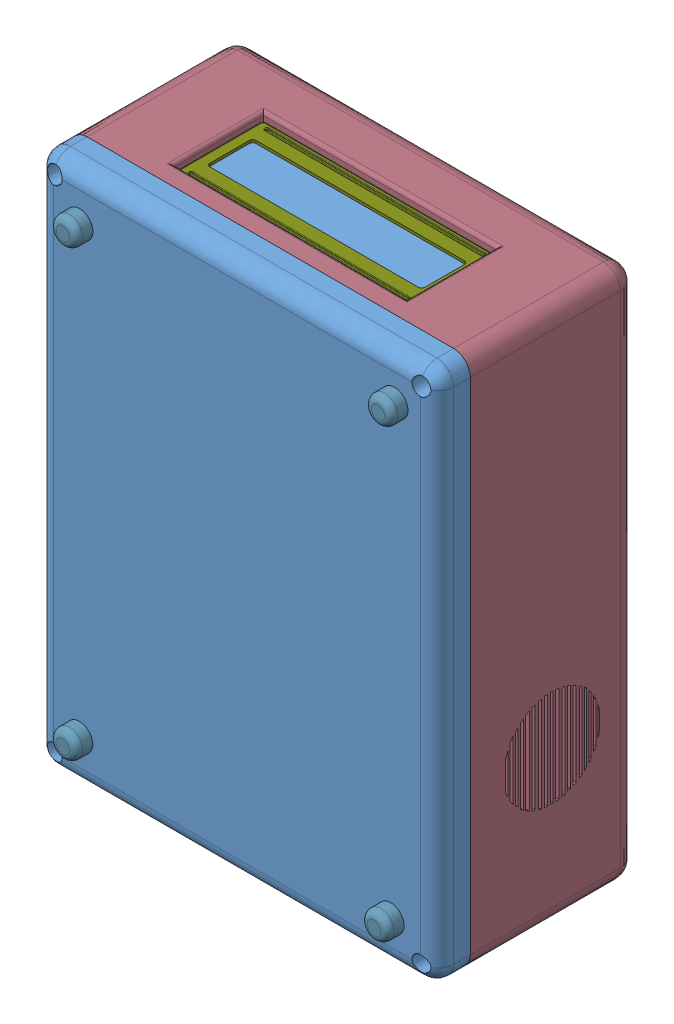
SolidWorks assembly Final enclosure for alarm clock, configuration Default. Lengths in mm.
Overall size (120 160 92.06).
262 component instances, 70 part files, 43 mates.
Components (placement in the parent):
- base-1: base [Default] at (30.3532 151.9666 91.7947) size (120 160 10)
- pin-8: pin [Default] at (46.9943 121.1307 93.7947) x (-0.999904 0.013854 0) z (0 0 -1) size (10 10 11.36)
- pin-9: pin [Default] at (96.9053 120.7497 93.7947) x (-0.30944 0.950919 0) z (0 0 -1) size (10 10 11.36)
- pin-10: pin [Default] at (46.2323 24.8647 93.7947) x (-0.51839 0.855144 0) z (0 0 -1) size (10 10 11.36)
- pin-11: pin [Default] at (99.0643 23.5947 93.7947) x (-0.211166 0.97745 0) z (0 0 -1) size (10 10 11.36)
- cct-4: cct [Default] at (154.3093 164.9457 90.0232) x (0 -1 0) z (0 0 -1) size (104.39 59.56 29)
  - Alarm_Clock.step-1: Alarm_Clock.step [Default] at origin size (104.39 59.56 29)
    - Board.step-1: Board.step [Default] at origin size (104.39 59.56 0.41)
      - Open CASCADE STEP translator 6.8 1.1.1.step-1: Open CASCADE STEP translator 6.8 1.1.1.step [Default] at (0 0 -0.4115) size (104.39 59.56 0.41)
    - P6.step-1: P6.step [Default] at origin size (15.65 5.57 13.08)
      - 66200411122.step-1: 66200411122.step [Default] at (71.0674 60.0699 4.98) x (1 0 0) z (0 1 0) size (15.65 13.08 5.57)
        - 6620xx11122_PIN.step-1: 6620xx11122_PIN.step [Default] at (-4.5 1.3806 0.255) x (-1 0 0) z (0 0 -1) size (0.64 10.1 0.9)
        - 6620xx11122_PIN.step-2: 6620xx11122_PIN.step [Default] at (-1.5 1.3806 0.255) size (0.64 10.1 0.9)
        - 6620xx11122_PIN.step-3: 6620xx11122_PIN.step [Default] at (1.5 1.3806 0.255) x (-1 0 0) z (0 0 -1) size (0.64 10.1 0.9)
        - 6620xx11122_PIN.step-4: 6620xx11122_PIN.step [Default] at (4.5 1.3806 0.255) size (0.64 10.1 0.9)
        - 66200411122-0.step-1: 66200411122-0.step [Default] at origin size (15.65 11 5.57)
    - U2.step-1: U2.step [Default] at origin size (7.2 35.3 4.58)
      - 5917139056.step-1: 5917139056.step [Default] at (93.091 78.74 0) size (7.2 35.3 4.58)
        - Extruded.step-1: Extruded.step [Default] at origin size (7.2 35.3 4.58)
    - U1.step-1: U1.step [Default] at origin size (10.5 4.7 16.2)
      - 5917143376.step-1: 5917143376.step [Default] at (61.468 81.322 3.5) size (10.5 4.7 9.55)
        - Extruded-1.step-1: Extruded-1.step [Default] at origin size (10.5 4.7 9.55)
      - 5917143056.step-1: 5917143056.step [Default] at (61.468 82.972 13.05) size (10.4 1.3 6.65)
        - Extruded-2.step-1: Extruded-2.step [Default] at origin size (10.4 1.3 6.65)
    - SW1.step-1: SW1.step [Default] at origin size (7.8 5.99 8.11)
      - Switch_TE_1825910-2_eec.step-1: Switch_TE_1825910-2_eec.step [Default] at (81.407 101.6 0) size (7.8 5.99 8.11)
        - Body.step-1: Body.step [Default] at (0 0 4.3) x (0 -1 0) z (0 0 1) size (5.99 5.99 3.9)
        - button.step-1: button.step [Default] at (0 0 4.3) x (0 -1 0) z (0 0 1) size (3.51 3.51 1.1)
        - cover.step-1: cover.step [Default] at (0 0 4.3) x (0 -1 0) z (0 0 1) size (5.99 5.99 0.1)
        - leads.step-1: leads.step [Default] at (0 0 4.3) x (0 -1 0) z (0 0 1) size (5.21 7.8 4.81)
        - circle.step-1: circle.step [Default] at (-2.6803 2.6863 3.6) size (0.4 0.4 0)
        - TE_Connectivity.step-1: TE_Connectivity.step [Default] at (-0.1925 -2.4218 3.6) size (2.27 0.85 0.01)
    - R9.step-1: R9.step [Default] at origin size (3.9 15.83 5.9)
      - 5917146656.step-1: 5917146656.step [Default] at (131.699 58.921 1.95) x (0 0 -1) z (0 1 0) size (0.83 0.83 15)
        - Cylinder.step-1: Cylinder.step [Default] at origin size (0.83 0.83 15)
      - 5917146416.step-1: 5917146416.step [Default] at (131.6989 73.9211 1.95) x (0 1 0) z (0 0 1) size (0.83 0.83 0.83)
        - Sphere.step-1: Sphere.step [Default] at origin size (0.83 0.83 0.83)
      - 5917146416.step-2: 5917146416.step [Default] at (131.699 58.921 1.95) x (0 1 0) z (0 0 1) size (0.83 0.83 0.83)
        - Sphere.step-1: Sphere.step [Default] at origin size (0.83 0.83 0.83)
      - 5917146016.step-1: 5917146016.step [Default] at (131.6989 73.9211 -2) x (0 1 0) z (0 0 1) size (0.83 0.83 3.95)
        - Cylinder-3.step-1: Cylinder-3.step [Default] at origin size (0.83 0.83 3.95)
      - 5917146016.step-2: 5917146016.step [Default] at (131.699 58.9211 -2) x (0 1 0) z (0 0 1) size (0.83 0.83 3.95)
        - Cylinder-3.step-1: Cylinder-3.step [Default] at origin size (0.83 0.83 3.95)
      - 5917145616.step-1: 5917145616.step [Default] at (131.699 61.4209 1.95) x (0 0 -1) z (0 1 0) size (3.9 3.9 10)
        - Cylinder-4.step-1: Cylinder-4.step [Default] at origin size (3.9 3.9 10)
    - R8.step-1: R8.step [Default] at origin size (3.9 15.83 5.9)
      - 5917145616.step-1: 5917145616.step [Default] at (118.745 61.4209 1.95) x (0 0 -1) z (0 1 0) size (3.9 3.9 10)
        - Cylinder-4.step-1: Cylinder-4.step [Default] at origin size (3.9 3.9 10)
      - 5917146016.step-1: 5917146016.step [Default] at (118.745 58.9211 -2) x (0 1 0) z (0 0 1) size (0.83 0.83 3.95)
        - Cylinder-3.step-1: Cylinder-3.step [Default] at origin size (0.83 0.83 3.95)
      - 5917146016.step-2: 5917146016.step [Default] at (118.7449 73.9211 -2) x (0 1 0) z (0 0 1) size (0.83 0.83 3.95)
        - Cylinder-3.step-1: Cylinder-3.step [Default] at origin size (0.83 0.83 3.95)
      - 5917146416.step-1: 5917146416.step [Default] at (118.745 58.921 1.95) x (0 1 0) z (0 0 1) size (0.83 0.83 0.83)
        - Sphere.step-1: Sphere.step [Default] at origin size (0.83 0.83 0.83)
      - 5917146416.step-2: 5917146416.step [Default] at (118.7449 73.9211 1.95) x (0 1 0) z (0 0 1) size (0.83 0.83 0.83)
        - Sphere.step-1: Sphere.step [Default] at origin size (0.83 0.83 0.83)
      - 5917146656.step-1: 5917146656.step [Default] at (118.745 58.921 1.95) x (0 0 -1) z (0 1 0) size (0.83 0.83 15)
        - Cylinder.step-1: Cylinder.step [Default] at origin size (0.83 0.83 15)
    - R7.step-1: R7.step [Default] at origin size (3.9 15.83 5.9)
      - 5917145616.step-1: 5917145616.step [Default] at (125.476 61.2939 1.95) x (0 0 -1) z (0 1 0) size (3.9 3.9 10)
        - Cylinder-4.step-1: Cylinder-4.step [Default] at origin size (3.9 3.9 10)
      - 5917146016.step-1: 5917146016.step [Default] at (125.476 58.7941 -2) x (0 1 0) z (0 0 1) size (0.83 0.83 3.95)
        - Cylinder-3.step-1: Cylinder-3.step [Default] at origin size (0.83 0.83 3.95)
      - 5917146016.step-2: 5917146016.step [Default] at (125.4759 73.7941 -2) x (0 1 0) z (0 0 1) size (0.83 0.83 3.95)
        - Cylinder-3.step-1: Cylinder-3.step [Default] at origin size (0.83 0.83 3.95)
      - 5917146416.step-1: 5917146416.step [Default] at (125.476 58.794 1.95) x (0 1 0) z (0 0 1) size (0.83 0.83 0.83)
        - Sphere.step-1: Sphere.step [Default] at origin size (0.83 0.83 0.83)
      - 5917146416.step-2: 5917146416.step [Default] at (125.4759 73.7941 1.95) x (0 1 0) z (0 0 1) size (0.83 0.83 0.83)
        - Sphere.step-1: Sphere.step [Default] at origin size (0.83 0.83 0.83)
      - 5917146656.step-1: 5917146656.step [Default] at (125.476 58.794 1.95) x (0 0 -1) z (0 1 0) size (0.83 0.83 15)
        - Cylinder.step-1: Cylinder.step [Default] at origin size (0.83 0.83 15)
    - R6.step-1: R6.step [Default] at origin size (3.9 15.83 5.9)
      - 5917145616.step-1: 5917145616.step [Default] at (138.43 61.3009 1.95) x (0 0 -1) z (0 1 0) size (3.9 3.9 10)
        - Cylinder-4.step-1: Cylinder-4.step [Default] at origin size (3.9 3.9 10)
      - 5917146016.step-1: 5917146016.step [Default] at (138.43 58.8011 -2) x (0 1 0) z (0 0 1) size (0.83 0.83 3.95)
        - Cylinder-3.step-1: Cylinder-3.step [Default] at origin size (0.83 0.83 3.95)
      - 5917146016.step-2: 5917146016.step [Default] at (138.4299 73.8011 -2) x (0 1 0) z (0 0 1) size (0.83 0.83 3.95)
        - Cylinder-3.step-1: Cylinder-3.step [Default] at origin size (0.83 0.83 3.95)
      - 5917146416.step-1: 5917146416.step [Default] at (138.43 58.801 1.95) x (0 1 0) z (0 0 1) size (0.83 0.83 0.83)
        - Sphere.step-1: Sphere.step [Default] at origin size (0.83 0.83 0.83)
      - 5917146416.step-2: 5917146416.step [Default] at (138.4299 73.8011 1.95) x (0 1 0) z (0 0 1) size (0.83 0.83 0.83)
        - Sphere.step-1: Sphere.step [Default] at origin size (0.83 0.83 0.83)
      - 5917146656.step-1: 5917146656.step [Default] at (138.43 58.801 1.95) x (0 0 -1) z (0 1 0) size (0.83 0.83 15)
        - Cylinder.step-1: Cylinder.step [Default] at origin size (0.83 0.83 15)
    - R5.step-1: R5.step [Default] at origin size (15.83 3.9 5.9)
      - 5919244592.step-1: 5919244592.step [Default] at (63.634 105.156 1.95) x (0 0 -1) z (-1 0 0) size (0.83 0.83 15)
        - Cylinder-5.step-1: Cylinder-5.step [Default] at origin size (0.83 0.83 15)
      - 5919245152.step-1: 5919245152.step [Default] at (48.6339 105.1559 1.95) x (-1 0 0) z (0 0 1) size (0.83 0.83 0.83)
        - Sphere-6.step-1: Sphere-6.step [Default] at origin size (0.83 0.83 0.83)
      - 5919245152.step-2: 5919245152.step [Default] at (63.634 105.156 1.95) x (-1 0 0) z (0 0 1) size (0.83 0.83 0.83)
        - Sphere-6.step-1: Sphere-6.step [Default] at origin size (0.83 0.83 0.83)
      - 5919245872.step-1: 5919245872.step [Default] at (48.6339 105.1559 -2) x (-1 0 0) z (0 0 1) size (0.83 0.83 3.95)
        - Cylinder-7.step-1: Cylinder-7.step [Default] at origin size (0.83 0.83 3.95)
      - 5919245872.step-2: 5919245872.step [Default] at (63.6339 105.156 -2) x (-1 0 0) z (0 0 1) size (0.83 0.83 3.95)
        - Cylinder-7.step-1: Cylinder-7.step [Default] at origin size (0.83 0.83 3.95)
      - 5919246432.step-1: 5919246432.step [Default] at (61.1341 105.156 1.95) x (0 0 -1) z (-1 0 0) size (3.9 3.9 10)
        - Cylinder-8.step-1: Cylinder-8.step [Default] at origin size (3.9 3.9 10)
    - R4.step-1: R4.step [Default] at origin size (15.83 3.9 5.9)
      - 5919246432.step-1: 5919246432.step [Default] at (138.0961 79.756 1.95) x (0 0 -1) z (-1 0 0) size (3.9 3.9 10)
        - Cylinder-8.step-1: Cylinder-8.step [Default] at origin size (3.9 3.9 10)
      - 5919245872.step-1: 5919245872.step [Default] at (140.5959 79.756 -2) x (-1 0 0) z (0 0 1) size (0.83 0.83 3.95)
        - Cylinder-7.step-1: Cylinder-7.step [Default] at origin size (0.83 0.83 3.95)
      - 5919245872.step-2: 5919245872.step [Default] at (125.5959 79.7559 -2) x (-1 0 0) z (0 0 1) size (0.83 0.83 3.95)
        - Cylinder-7.step-1: Cylinder-7.step [Default] at origin size (0.83 0.83 3.95)
      - 5919245152.step-1: 5919245152.step [Default] at (140.5959 79.756 1.95) x (-1 0 0) z (0 0 1) size (0.83 0.83 0.83)
        - Sphere-6.step-1: Sphere-6.step [Default] at origin size (0.83 0.83 0.83)
      - 5919245152.step-2: 5919245152.step [Default] at (125.5959 79.7559 1.95) x (-1 0 0) z (0 0 1) size (0.83 0.83 0.83)
        - Sphere-6.step-1: Sphere-6.step [Default] at origin size (0.83 0.83 0.83)
      - 5919244592.step-1: 5919244592.step [Default] at (140.596 79.756 1.95) x (0 0 -1) z (-1 0 0) size (0.83 0.83 15)
        - Cylinder-5.step-1: Cylinder-5.step [Default] at origin size (0.83 0.83 15)
    - R1.step-1: R1.step [Default] at origin size (15.83 3.9 5.9)
      - 5919244592.step-1: 5919244592.step [Default] at (74.168 100.457 1.95) x (0 0 -1) z (-1 0 0) size (0.83 0.83 15)
        - Cylinder-5.step-1: Cylinder-5.step [Default] at origin size (0.83 0.83 15)
      - 5919245152.step-1: 5919245152.step [Default] at (59.1679 100.4569 1.95) x (-1 0 0) z (0 0 1) size (0.83 0.83 0.83)
        - Sphere-6.step-1: Sphere-6.step [Default] at origin size (0.83 0.83 0.83)
      - 5919245152.step-2: 5919245152.step [Default] at (74.168 100.457 1.95) x (-1 0 0) z (0 0 1) size (0.83 0.83 0.83)
        - Sphere-6.step-1: Sphere-6.step [Default] at origin size (0.83 0.83 0.83)
      - 5919245872.step-1: 5919245872.step [Default] at (59.1679 100.4569 -2) x (-1 0 0) z (0 0 1) size (0.83 0.83 3.95)
        - Cylinder-7.step-1: Cylinder-7.step [Default] at origin size (0.83 0.83 3.95)
      - 5919245872.step-2: 5919245872.step [Default] at (74.1679 100.457 -2) x (-1 0 0) z (0 0 1) size (0.83 0.83 3.95)
        - Cylinder-7.step-1: Cylinder-7.step [Default] at origin size (0.83 0.83 3.95)
      - 5919246432.step-1: 5919246432.step [Default] at (71.6681 100.457 1.95) x (0 0 -1) z (-1 0 0) size (3.9 3.9 10)
        - Cylinder-8.step-1: Cylinder-8.step [Default] at origin size (3.9 3.9 10)
    - Q1.step-1: Q1.step [Default] at origin size (4.79 3.67 5.95)
      - 5917134816.step-1: 5917134816.step [Default] at (121.793 99.457 2.54) size (4.79 3.67 5.95)
        - Extruded-9.step-1: Extruded-9.step [Default] at origin size (4.79 3.67 5.95)
    - P5.step-1: P5.step [Default] at origin size (5.08 5.8 15.26)
      - 022272021.step-1: 022272021.step [Default] at (132.9691 104.0131 1.6) x (1 0 0) z (0 -1 0) size (5.08 15.26 5.8)
        - Open CASCADE STEP translator 6.8 1.14.1.1.step-1: Open CASCADE STEP translator 6.8 1.14.1.1.step [Default] at origin size (5.08 15.26 5.8)
        - Open CASCADE STEP translator 6.8 1.14.1.2.step-1: Open CASCADE STEP translator 6.8 1.14.1.2.step [Default] at origin
    - P4.step-1: P4.step [Default] at origin size (5.57 21.65 13.75)
      - 66200611122.step-1: 66200611122.step [Default] at (108.0759 64.1086 4.98) x (0 -1 0) z (1 0 0) size (21.65 13.75 5.57)
        - 6620xx11122_PIN-10.step-1: 6620xx11122_PIN-10.step [Default] at (-7.5 1.3806 0.255) x (-1 0 0) z (0 0 -1) size (0.64 10.1 0.9)
        - 6620xx11122_PIN-10.step-2: 6620xx11122_PIN-10.step [Default] at (-4.5 1.3806 0.255) size (0.64 10.1 0.9)
        - 6620xx11122_PIN-10.step-3: 6620xx11122_PIN-10.step [Default] at (-1.5 2.0477 0.25) x (-1 0 0) z (0 0 -1) size (0.64 10.1 0.9)
        - 6620xx11122_PIN-10.step-4: 6620xx11122_PIN-10.step [Default] at (1.5 2.0477 0.25) size (0.64 10.1 0.9)
        - 6620xx11122_PIN-10.step-5: 6620xx11122_PIN-10.step [Default] at (4.5 2.0477 0.25) x (-1 0 0) z (0 0 -1) size (0.64 10.1 0.9)
        - 6620xx11122_PIN-10.step-6: 6620xx11122_PIN-10.step [Default] at (7.5 2.0477 0.25) size (0.64 10.1 0.9)
        - 66200611122-11.step-1: 66200611122-11.step [Default] at origin size (21.65 11 5.57)
    - P3.step-1: P3.step [Default] at origin size (5.57 24.65 13.75)
      - 66200711122.step-1: 66200711122.step [Default] at (110.1101 90.3304 4.98) x (0 1 0) z (-1 0 0) size (24.65 13.75 5.57)
        - 6620xx11122_PIN-12.step-1: 6620xx11122_PIN-12.step [Default] at (-9 1.3806 0.255) x (-1 0 0) z (0 0 -1) size (0.64 10.1 0.9)
        - 6620xx11122_PIN-12.step-2: 6620xx11122_PIN-12.step [Default] at (-6 1.3806 0.255) size (0.64 10.1 0.9)
        - 6620xx11122_PIN-12.step-3: 6620xx11122_PIN-12.step [Default] at (-3 2.0477 0.25) x (-1 0 0) z (0 0 -1) size (0.64 10.1 0.9)
        - 6620xx11122_PIN-12.step-4: 6620xx11122_PIN-12.step [Default] at (0 2.0477 0.25) size (0.64 10.1 0.9)
        - 6620xx11122_PIN-12.step-5: 6620xx11122_PIN-12.step [Default] at (3 2.0477 0.25) x (-1 0 0) z (0 0 -1) size (0.64 10.1 0.9)
        - 6620xx11122_PIN-12.step-6: 6620xx11122_PIN-12.step [Default] at (6 2.0477 0.25) size (0.64 10.1 0.9)
        - 6620xx11122_PIN-12.step-7: 6620xx11122_PIN-12.step [Default] at (9 2.0477 0.25) x (-1 0 0) z (0 0 -1) size (0.64 10.1 0.9)
        - 66200711122-13.step-1: 66200711122-13.step [Default] at origin size (24.65 11 5.57)
    - P2.step-1: P2.step [Default] at origin size (39.65 5.57 13.08)
      - 66201211122.step-1: 66201211122.step [Default] at (63.6486 91.8221 4.98) x (-1 0 0) z (0 -1 0) size (39.65 13.08 5.57)
        - 6620xx11122_PIN-14.step-1: 6620xx11122_PIN-14.step [Default] at (-16.5 1.3806 0.255) x (-1 0 0) z (0 0 -1) size (0.64 10.1 0.9)
        - 6620xx11122_PIN-14.step-2: 6620xx11122_PIN-14.step [Default] at (-13.5 1.3806 0.255) size (0.64 10.1 0.9)
        - 6620xx11122_PIN-14.step-3: 6620xx11122_PIN-14.step [Default] at (-10.5 1.3806 0.255) x (-1 0 0) z (0 0 -1) size (0.64 10.1 0.9)
        - 6620xx11122_PIN-14.step-4: 6620xx11122_PIN-14.step [Default] at (-4.5 1.3806 0.255) x (-1 0 0) z (0 0 -1) size (0.64 10.1 0.9)
        - 6620xx11122_PIN-14.step-5: 6620xx11122_PIN-14.step [Default] at (1.5 1.3806 0.255) x (-1 0 0) z (0 0 -1) size (0.64 10.1 0.9)
        - 6620xx11122_PIN-14.step-6: 6620xx11122_PIN-14.step [Default] at (7.5 1.3806 0.255) x (-1 0 0) z (0 0 -1) size (0.64 10.1 0.9)
        - 6620xx11122_PIN-14.step-7: 6620xx11122_PIN-14.step [Default] at (13.5 1.3806 0.255) x (-1 0 0) z (0 0 -1) size (0.64 10.1 0.9)
        - 6620xx11122_PIN-14.step-8: 6620xx11122_PIN-14.step [Default] at (-7.5 1.3806 0.255) size (0.64 10.1 0.9)
        - 6620xx11122_PIN-14.step-9: 6620xx11122_PIN-14.step [Default] at (-1.5 1.3806 0.255) size (0.64 10.1 0.9)
        - 6620xx11122_PIN-14.step-10: 6620xx11122_PIN-14.step [Default] at (4.5 1.3806 0.255) size (0.64 10.1 0.9)
        - 6620xx11122_PIN-14.step-11: 6620xx11122_PIN-14.step [Default] at (10.5 1.3806 0.255) size (0.64 10.1 0.9)
        - 6620xx11122_PIN-14.step-12: 6620xx11122_PIN-14.step [Default] at (16.5 1.3806 0.255) size (0.64 10.1 0.9)
        - 66201211122-15.step-1: 66201211122-15.step [Default] at origin size (39.65 11 5.57)
    - P1.step-1: P1.step [Default] at origin size (5.08 5.8 15.26)
      - 022272021.step-1: 022272021.step [Default] at (46.3549 81.4069 1.6) x (-1 0 0) z (0 1 0) size (5.08 15.26 5.8)
        - Open CASCADE STEP translator 6.8 1.14.1.1.step-1: Open CASCADE STEP translator 6.8 1.14.1.1.step [Default] at origin size (5.08 15.26 5.8)
        - Open CASCADE STEP translator 6.8 1.14.1.2.step-1: Open CASCADE STEP translator 6.8 1.14.1.2.step [Default] at origin
    - LS1.step-1: LS1.step [Default] at origin size (16 16 13.9)
      - Speak_TDK_SDC1610M5-01_eec.step-1: Speak_TDK_SDC1610M5-01_eec.step [Default] at (131.231 90.424 0) size (16 16 13.9)
        - 1.step-1: 1.step [Default] at origin size (5.8 0.8 4.4)
        - 2.step-1: 2.step [Default] at origin size (5 5 0.5)
        - 3.step-1: 3.step [Default] at origin size (16 16 10)
        - TDK_Logo.step-1: TDK_Logo.step [Default] at (0.0013 6.3762 9.999) size (4.12 1.23 0)
    - D1.step-1: D1.step [Default] at origin size (1.91 8.12 5.91)
      - Diode_ON_Semiconductor_1N914B_eec.step-1: Diode_ON_Semiconductor_1N914B_eec.step [Default] at (118.618 88.9 0) x (0 1 0) z (0 0 1) size (8.12 1.91 5.91)
        - 1-16.step-1: 1-16.step [Default] at (0 -0.955 0.955) size (0.88 1.91 1.91)
        - 2-17.step-1: 2-17.step [Default] at (0 -0.955 0.955) size (8.12 0.7 5.3)
        - 3-18.step-1: 3-18.step [Default] at (0 -0.955 0.955) size (3.8 1.91 1.91)
        - 4.step-1: 4.step [Default] at (0 -0.955 0.955) size (0.45 0.45 0.96)
    - C5.step-1: C5.step [Default] at origin size (2.54 3.81 11.66)
      - 5917146896.step-1: 5917146896.step [Default] at (72.3899 68.5801 -7) size (0.51 0.51 7)
        - Extruded-19.step-1: Extruded-19.step [Default] at origin size (0.51 0.51 7)
      - 5917146896.step-2: 5917146896.step [Default] at (72.39 71.1201 -7) size (0.51 0.51 7)
        - Extruded-19.step-1: Extruded-19.step [Default] at origin size (0.51 0.51 7)
      - 5917140256.step-1: 5917140256.step [Default] at (72.39 69.85 0) size (2.54 3.81 4.66)
        - Extruded-20.step-1: Extruded-20.step [Default] at origin size (2.54 3.81 4.66)
    - C4.step-1: C4.step [Default] at origin size (2.54 3.81 11.66)
      - 5917146896.step-1: 5917146896.step [Default] at (72.3899 78.1051 -7) size (0.51 0.51 7)
        - Extruded-19.step-1: Extruded-19.step [Default] at origin size (0.51 0.51 7)
      - 5917146896.step-2: 5917146896.step [Default] at (72.39 80.6451 -7) size (0.51 0.51 7)
        - Extruded-19.step-1: Extruded-19.step [Default] at origin size (0.51 0.51 7)
      - 5917140256.step-1: 5917140256.step [Default] at (72.39 79.375 0) size (2.54 3.81 4.66)
        - Extruded-20.step-1: Extruded-20.step [Default] at origin size (2.54 3.81 4.66)
    - C3.step-1: C3.step [Default] at origin size (8 8 25)
      - 5917142176.step-1: 5917142176.step [Default] at (97.7901 103.6321 -3) size (0.6 0.6 3)
        - Cylinder-21.step-1: Cylinder-21.step [Default] at origin size (0.6 0.6 3)
      - 5917141696.step-1: 5917141696.step [Default] at (101.29 103.6321 -2) size (0.6 0.6 2)
        - Cylinder-22.step-1: Cylinder-22.step [Default] at origin size (0.6 0.6 2)
      - 5917141296.step-1: 5917141296.step [Default] at (99.5401 103.6321 0) size (8 8 22)
        - Cylinder-23.step-1: Cylinder-23.step [Default] at origin size (8 8 22)
    - C2.step-1: C2.step [Default] at origin size (8 8 25)
      - 5917141056.step-1: 5917141056.step [Default] at (58.6741 69.6239 0) x (0 -1 0) z (0 0 1) size (8 8 22)
        - Cylinder-24.step-1: Cylinder-24.step [Default] at origin size (8 8 22)
      - 5917140816.step-1: 5917140816.step [Default] at (58.6741 67.874 -2) x (0 -1 0) z (0 0 1) size (0.6 0.6 2)
        - Cylinder-25.step-1: Cylinder-25.step [Default] at origin size (0.6 0.6 2)
      - 5917140576.step-1: 5917140576.step [Default] at (58.6741 71.3739 -3) x (0 -1 0) z (0 0 1) size (0.6 0.6 3)
        - Cylinder-26.step-1: Cylinder-26.step [Default] at origin size (0.6 0.6 3)
    - C1.step-1: C1.step [Default] at origin size (8 8 25)
      - 5917141056.step-1: 5917141056.step [Default] at (46.6091 69.6239 0) x (0 -1 0) z (0 0 1) size (8 8 22)
        - Cylinder-24.step-1: Cylinder-24.step [Default] at origin size (8 8 22)
      - 5917140816.step-1: 5917140816.step [Default] at (46.6091 67.874 -2) x (0 -1 0) z (0 0 1) size (0.6 0.6 2)
        - Cylinder-25.step-1: Cylinder-25.step [Default] at origin size (0.6 0.6 2)
      - 5917140576.step-1: 5917140576.step [Default] at (46.6091 71.3739 -3) x (0 -1 0) z (0 0 1) size (0.6 0.6 3)
        - Cylinder-26.step-1: Cylinder-26.step [Default] at origin size (0.6 0.6 3)
- 9V Battery Holder-2: 9V Battery Holder [Default] at (137.4118 101.1961 96.7947) x (-1 0 0) z (0 -1 0) size (30 20 54)
- Battery-3: Battery [Default] at (122.6618 51.3064 84.1947) size (26.5 48 17.2)
- body assem-1: body assem [Default] at (15.0156 -32.943 164.5173) x (1 0 0) z (0 1 0) size (120 50 160)
  - body-1: body [Default] at (15.3376 122.7226 24.9096) size (120 50 160)
  - LCD-1: LCD [Default] at (75.9876 93.6226 173.2096) x (1 0 0) z (0 -1 0) size (80 18.3 36)
    - pcbboard-1: pcbboard [Default] at origin size (80 4.2 36)
    - 16pin_header__-1: 16pin_header__ [Default] at (-32 0 -15.5) x (0 0 1) z (1 0 0) size (2.54 11.5 40.64)
    - lcd window-1: lcd window [Default] at (0 9 1.5) size (71.3 11.8 27.44)
    - backlight-1: backlight [Default] at (0 1.7 1.5) x (-1 0 0) z (0 0 -1) size (74.38 2.98 18)
    - conductor-1: conductor [Default] at (0 1.7 12.6) size (69.7 5.5 3)
    - conductor-2: conductor [Default] at (0 1.7 -9.6) size (69.7 5.5 3)
    - liquid crystal grabcad-1: liquid crystal grabcad [Default] at (0 7.9 1.5) size (68.5 2.2 25)
    - smt_resistor222-1: smt_resistor222 [Default] at (-32.75 0 -5.25) x (0 0 1) z (1 0 0) size (1.8 0.6 4)
    - smt_resistor222-2: smt_resistor222 [Default] at (-32.75 0 -2.75) x (0 0 1) z (1 0 0) size (1.8 0.6 4)
    - smt_resistor222-3: smt_resistor222 [Default] at (-32.75 0 -0.25) x (0 0 1) z (1 0 0) size (1.8 0.6 4)
    - smt_resistor222-4: smt_resistor222 [Default] at (-32.75 0 2.25) x (0 0 1) z (1 0 0) size (1.8 0.6 4)
    - smt_resistor222-5: smt_resistor222 [Default] at (-32.75 0 4.75) x (0 0 1) z (1 0 0) size (1.8 0.6 4)
    - smt_resistor222-6: smt_resistor222 [Default] at (-32.75 0 7.25) x (0 0 1) z (1 0 0) size (1.8 0.6 4)
    - smt_resistor101-1: smt_resistor101 [Default] at (30.25 0 6.1) x (0 0 -1) z (-1 0 0) size (1.8 0.6 5.2)
    - smt_resistor101-2: smt_resistor101 [Default] at (30.25 0 2.85) x (0 0 -1) z (-1 0 0) size (1.8 0.6 5.2)
  - pin1 lcd-1: pin1 lcd [Default] at (113.4876 109.1226 170.0096) size (3 3 5)
  - pin1 lcd-2: pin1 lcd [Default] at (113.4876 78.1226 170.0096) size (3 3 5)
  - pin1 lcd-3: pin1 lcd [Default] at (38.4876 78.1226 170.0096) size (3 3 5)
  - pin1 lcd-4: pin1 lcd [Default] at (38.4876 109.1226 170.0096) size (3 3 5)
- KeyPad_3x4_w_pcb-1: KeyPad_3x4_w_pcb [Default] at (91.866 94.3035 38.7947) x (1 0 0) z (0 0 -1) size (51 69.5 10.29)
  - KeyPad_3x4_w_pcb.step-1: KeyPad_3x4_w_pcb.step [Default] at origin size (51 69.5 10.29)
    - Body_top.step-1: Body_top.step [Default] at origin size (46 56.8 3.6)
    - KeyPad.step-1: KeyPad.step [Default] at origin size (44.02 53.35 7.29)
    - Body_bottom.step-1: Body_bottom.step [Default] at origin size (51 63.8 3)
    - PCB_pads.step-1: PCB_pads.step [Default] at origin size (36.4 5.6 1.61)
    - PCB.step-1: PCB.step [Default] at origin size (36.5 5.7 1.6)
    - PCBtracks.step-1: PCBtracks.step [Default] at origin size (36.45 5.65 1.6)
    - KeyPad_collor.step-1: KeyPad_collor.step [Default] at origin size (40 50 6.89)
- Emergency Stop Button-2: Emergency Stop Button [Default] at (90.3533 26.9639 34.7353) x (0.999972 0.007536 0) z (-0.007536 0.999972 0) size (38.72 65.6 38.72)
- STP310400160-1: STP310400160 [Default] at (68.791 64.7287 37.5551) x (1 0 0) z (0 1 0) size (6.25 12.93 6.25)
- STP310400160-2: STP310400160 [Default] at (114.941 64.7287 37.5551) x (1 0 0) z (0 1 0) size (6.25 12.93 6.25)
- STP310400160-3: STP310400160 [Default] at (68.791 123.8787 37.5551) x (1 0 0) z (0 1 0) size (6.25 12.93 6.25)
- STP310400160-4: STP310400160 [Default] at (114.941 123.8787 37.5551) x (1 0 0) z (0 1 0) size (6.25 12.93 6.25)
- STP310400160-6: STP310400160 [Default] at (35.3531 -3.0336 98.0342) x (0.929608 -0.36855 0) z (-0.36855 -0.929608 0) size (6.25 12.93 6.25)
- STP310400160-7: STP310400160 [Default] at (145.3531 146.9664 98.0342) x (0.929608 -0.36855 0) z (-0.36855 -0.929608 0) size (6.25 12.93 6.25)
- STP310400160-9: STP310400160 [Default] at (35.3531 146.9664 98.0342) x (0.929608 -0.36855 0) z (-0.36855 -0.929608 0) size (6.25 12.93 6.25)
- STP310400160-10: STP310400160 [Default] at (145.3531 -3.0336 98.0342) x (0.929608 -0.36855 0) z (-0.36855 -0.929608 0) size (6.25 12.93 6.25)
- leg-5: leg [Default] at (43.0816 4.9248 106.7947) x (-0.998999 -0.044741 0) z (0 0 -1) size (8 8 5)
- leg-6: leg [Default] at (137.6443 139.0201 106.7947) x (-0.998999 -0.044741 0) z (0 0 -1) size (8 8 5)
- leg-7: leg [Default] at (136.4751 4.5046 106.7947) x (-0.998999 -0.044741 0) z (0 0 -1) size (8 8 5)
- leg-8: leg [Default] at (43.1186 138.1725 106.7947) x (-0.998999 -0.044741 0) z (0 0 -1) size (8 8 5)
- cover-1: cover [Default] at (109.9211 133.9035 40.1947) x (-1 0 0) z (0 0 -1) size (36.3 5.6 3.6)
Mates (geometry in assembly coordinates):
- Parallel5: parallel: plane of base-1 through (30.3532 151.9666 96.7947) normal (0 0 -1); plane of pin-8 through (46.9943 121.1307 96.7947) normal (0 0 1)
- Parallel6: parallel: plane of base-1 through (30.3532 151.9666 96.7947) normal (0 0 -1); plane of pin-9 through (96.9053 120.7497 96.7947) normal (0 0 1)
- Coincident18: coincident: plane of base-1 through (30.3532 151.9666 96.7947) normal (0 0 -1); plane of pin-9 through (96.9053 120.7497 96.7947) normal (0 0 1)
- Coincident19: coincident: plane of base-1 through (30.3532 151.9666 96.7947) normal (0 0 -1); plane of pin-9 through (96.9053 120.7497 96.7947) normal (0 0 1)
- Coincident20: coincident: plane of base-1 through (30.3532 151.9666 96.7947) normal (0 0 -1); plane of pin-8 through (46.9943 121.1307 96.7947) normal (0 0 1)
- Coincident21: coincident: plane of base-1 through (30.3532 151.9666 96.7947) normal (0 0 -1); plane of pin-10 through (46.2323 24.8647 96.7947) normal (0 0 1)
- Coincident22: coincident: plane of base-1 through (30.3532 151.9666 96.7947) normal (0 0 -1); circle of pin-11
- Concentric5: concentric: circle of pin-8; circle of cct-4/Alarm_Clock.step-1/Board.step-1/Open CASCADE STEP translator 6.8 1.1.1.step-1
- Concentric7: concentric: circle of pin-9; circle of cct-4/Alarm_Clock.step-1/Board.step-1/Open CASCADE STEP translator 6.8 1.1.1.step-1
- Coincident24: coincident: plane of pin-9 through (96.9053 120.7497 90.4347) normal (0 0 -1); plane of cct-4/Alarm_Clock.step-1/Board.step-1/Open CASCADE STEP translator 6.8 1.1.1.step-1 through (102.4933 124.9407 90.4347) normal (0 0 1)
- Coincident26: coincident: plane of base-1 through (30.3532 151.9666 96.7947) normal (0 0 -1); plane of 9V Battery Holder-2 through (137.4118 101.1961 96.7947) normal (0 0 1)
- Parallel8: parallel: line of base-1 through (140.3532 136.9666 91.7947) axis (0 -1 0); line of 9V Battery Holder-2 through (137.4118 52.1961 94.7947) axis (0 1 0)
- Coincident37: coincident: plane of 9V Battery Holder-2 through (137.4118 101.1961 92.7947) normal (0 0 -1); plane of Battery-3 through (111.4118 96.3064 92.7947) normal (0 0 1)
- Coincident39: coincident: plane of Battery-3 through (109.4118 96.3064 90.7947) normal (-1 0 0); plane of 9V Battery Holder-2 through (109.4118 74.1961 154.828) normal (1 0 0)
- Coincident40: coincident: plane of base-1 through (30.3532 151.9666 91.7947) normal (0 0 -1); plane of body assem-1/body-1 through (30.3532 151.9666 91.7947) normal (0 0 1)
- Coincident41: coincident: line of base-1 through (145.3532 151.9666 91.7947) axis (-1 0 0); line of body assem-1/body-1 through (35.3532 151.9666 91.7947) axis (1 0 0)
- Coincident42: coincident: line of base-1 through (150.3532 -3.0334 91.7947) axis (0 1 0); line of body assem-1/body-1 through (150.3532 146.9666 91.7947) axis (0 -1 0)
- Coincident43: coincident: plane of body assem-1/body-1 through (30.3532 151.9666 41.7947) normal (0 0 -1); plane of KeyPad_3x4_w_pcb-1/KeyPad_3x4_w_pcb.step-1/Body_bottom.step-1 through (91.866 93.5526 41.7947) normal (0 0 1)
- Parallel9: parallel: line of body assem-1/body-1 through (35.3532 -3.0334 41.7947) axis (0 1 0); line of KeyPad_3x4_w_pcb-1/KeyPad_3x4_w_pcb.step-1/Body_bottom.step-1 through (66.366 124.0035 38.7947) axis (0 -1 0)
- Coincident45: coincident: plane of body assem-1/body-1 through (30.3532 151.9666 41.7947) normal (0 0 -1); plane of Emergency Stop Button-2 through (75.3912 26.8539 41.7947) normal (0 0 1)
- Concentric8: concentric: circle of body assem-1/body-1; circle of Emergency Stop Button-2
- Coincident50: coincident: plane of KeyPad_3x4_w_pcb-1/KeyPad_3x4_w_pcb.step-1/Body_bottom.step-1 through (91.866 93.5526 38.7947) normal (0 0 -1); plane of STP310400160-1 through (68.791 66.2179 38.7947) normal (0 0 1)
- Coincident51: coincident: plane of KeyPad_3x4_w_pcb-1/KeyPad_3x4_w_pcb.step-1/Body_bottom.step-1 through (91.866 93.5526 38.7947) normal (0 0 -1); plane of STP310400160-2 through (114.941 66.2179 38.7947) normal (0 0 1)
- Coincident52: coincident: plane of KeyPad_3x4_w_pcb-1/KeyPad_3x4_w_pcb.step-1/Body_bottom.step-1 through (91.866 93.5526 38.7947) normal (0 0 -1); plane of STP310400160-3 through (68.791 125.3679 38.7947) normal (0 0 1)
- Coincident53: coincident: plane of KeyPad_3x4_w_pcb-1/KeyPad_3x4_w_pcb.step-1/Body_bottom.step-1 through (91.866 93.5526 38.7947) normal (0 0 -1); plane of STP310400160-4 through (114.941 125.3679 38.7947) normal (0 0 1)
- Concentric10: concentric: circle of body assem-1/body-1; circle of STP310400160-1
- Concentric11: concentric: circle of KeyPad_3x4_w_pcb-1/KeyPad_3x4_w_pcb.step-1/Body_bottom.step-1; circle of STP310400160-2
- Concentric12: concentric: circle of KeyPad_3x4_w_pcb-1/KeyPad_3x4_w_pcb.step-1/Body_bottom.step-1; circle of STP310400160-4
- Concentric13: concentric: circle of KeyPad_3x4_w_pcb-1/KeyPad_3x4_w_pcb.step-1/Body_bottom.step-1; circle of STP310400160-3
- Coincident54: coincident: plane of base-1 through (35.3532 -3.0334 96.7947) normal (0 0 1); circle of STP310400160-6
- Concentric14: concentric: circle of base-1; circle of STP310400160-6
- Coincident55: coincident: plane of base-1 through (35.3532 146.9666 96.7947) normal (0 0 1); plane of STP310400160-9 through (34.8043 145.582 96.7947) normal (0 0 -1)
- Concentric15: concentric: circle of base-1; circle of STP310400160-9
- Coincident56: coincident: plane of base-1 through (145.3532 146.9666 96.7947) normal (0 0 1); plane of STP310400160-7 through (144.8043 145.582 96.7947) normal (0 0 -1)
- Concentric16: concentric: circle of base-1; circle of STP310400160-7
- Coincident59: coincident: plane of base-1 through (145.3532 -3.0334 96.7947) normal (0 0 1); plane of STP310400160-10 through (144.8043 -4.418 96.7947) normal (0 0 -1)
- Concentric17: concentric: circle of base-1; circle of STP310400160-10
- Coincident60: coincident: plane of base-1 through (30.3532 151.9666 101.7947) normal (0 0 1); plane of leg-5 through (43.0816 4.9248 101.7947) normal (0 0 -1)
- Coincident61: coincident: plane of base-1 through (30.3532 151.9666 101.7947) normal (0 0 1); plane of leg-6 through (137.6443 139.0201 101.7947) normal (0 0 -1)
- Coincident62: coincident: plane of base-1 through (30.3532 151.9666 101.7947) normal (0 0 1); plane of leg-8 through (43.1186 138.1725 101.7947) normal (0 0 -1)
- Coincident63: coincident: plane of base-1 through (30.3532 151.9666 101.7947) normal (0 0 1); plane of leg-7 through (136.4751 4.5046 101.7947) normal (0 0 -1)
- Coincident67: coincident: plane of body assem-1/body-1 through (30.3532 151.9666 41.7947) normal (0 0 -1); plane of cover-1 through (109.9211 133.9035 41.7947) normal (0 0 1)
- Coincident68: coincident: plane of KeyPad_3x4_w_pcb-1/KeyPad_3x4_w_pcb.step-1/PCB.step-1 through (110.116 131.9035 41.7947) normal (0 1 0); plane of cover-1 through (73.6211 131.9035 41.7947) normal (0 -1 0)
